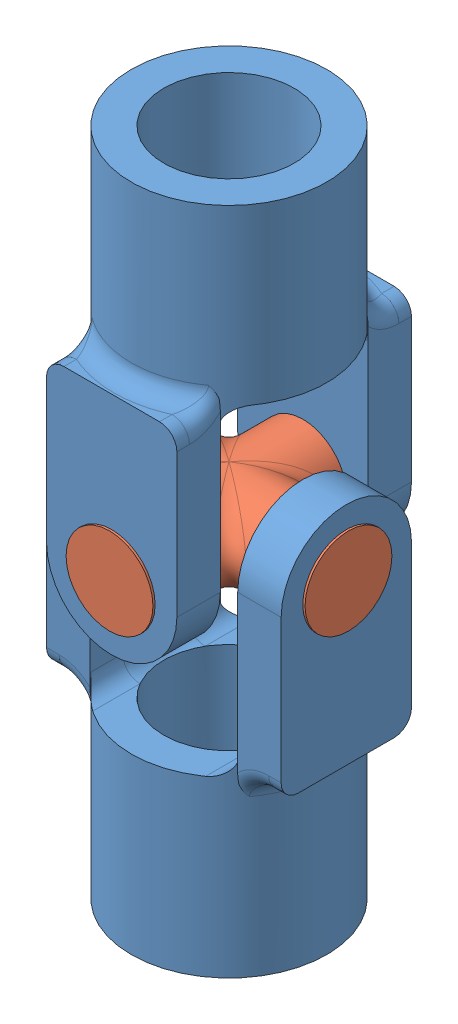
SolidWorks assembly Single U-Joint, configuration Default. Lengths in mm.
Overall size (34.92 97.79 34.92).
3 component instances, 2 part files, 4 mates.
Components (placement in the parent):
- U-Joint Housing-1: U-Joint Housing [Default] at origin size (34.29 58.42 28.57)
- U-Joint Cross-1: U-Joint Cross [Default] at (0 23.495 0) size (34.92 12.7 34.92)
- U-Joint Housing-2: U-Joint Housing [Default] at (0 46.99 0) x (0 0 -1) z (-1 0 0) size (34.29 58.42 28.57)
Mates (geometry in assembly coordinates):
- Concentric1: concentric anti-aligned: cylinder of U-Joint Housing-1 through (-17.145 23.495 0) axis (1 0 0) radius 6.35; cylinder of U-Joint Cross-1 through (17.4625 23.495 0) axis (-1 0 0) radius 6.35
- Width1: width anti-aligned: plane of U-Joint Cross-1 through (17.4625 23.495 0) normal (1 0 0); plane of U-Joint Housing-1 through (-17.4625 23.495 0) normal (-1 0 0); plane of U-Joint Cross-1 through (-17.145 0 9.525) normal (-1 0 0); plane of U-Joint Housing-1 through (17.145 0 9.525) normal (1 0 0)
- Concentric2: concentric aligned: cylinder of U-Joint Cross-1 through (0 23.495 17.4625) axis (0 0 -1) radius 6.35; cylinder of U-Joint Housing-2 through (0 23.495 17.145) axis (0 0 -1) radius 6.35
- Width2: width anti-aligned: plane of U-Joint Housing-2 through (-9.525 46.99 17.145) normal (0 0 1); plane of U-Joint Cross-1 through (-9.525 46.99 -17.145) normal (0 0 -1); plane of U-Joint Housing-2 through (0 23.495 -17.4625) normal (0 0 -1); plane of U-Joint Cross-1 through (0 23.495 17.4625) normal (0 0 1)
